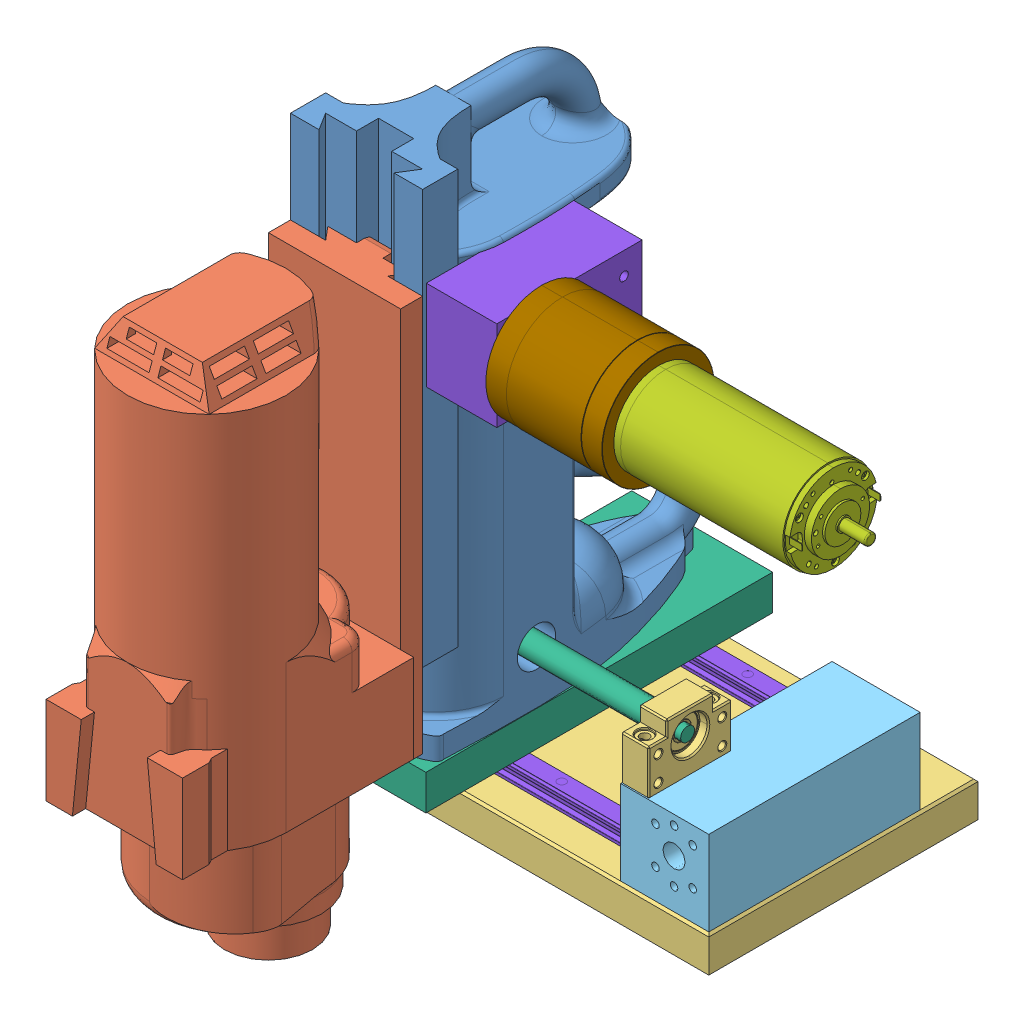
SolidWorks assembly Drill Assembly.12.21.2020, configuration Default. Lengths in mm.
Overall size (544.24 450.85 424.08).
33 component instances, 28 part files, 27 mates.
Components (placement in the parent):
- DrillPressRough-1: DrillPressRough [Default] at (-368.4719 -220.6024 612.8158) x (1 0 0) z (0 1 0) size (105.96 250.99 361.95)
- Motor-1: Motor [Default] at (-110.8779 -309.5024 330.761) x (-1 0 0) z (0 -1 0) size (114.3 193.67 403.23)
- ScrewAssembly_15cm_TOP-1: ScrewAssembly_15cm_TOP [Default] at (-199.8075 -207.5024 157.886) x (0 0 -1) z (1 0 0) size (61 107.5 369.65)
  - BF12.step-1: BF12.step [Default] at (-30 0 240.25) size (60 43 20)
  - BK12.step-1: BK12.step [Default] at (-30 0 12.5) size (60 43 30.65)
  - RM1605 Ball Nut STEP.step-1: RM1605 Ball Nut STEP.step [Default] at (-30 25 30.15) x (0 0 1) z (0 -1 0) size (42 48 40)
  - RM1605-1: RM1605 [Smaller Versionn] at (-30 25 248.25) x (-0.470167 -0.882577 0) z (0 0 -1) size (16 16 275.75)
  - Carriage-1: Carriage [Default] at (-30 -62.5 159.8307) x (1 0 0) z (0 1 0) size (52 63.99 19.5)
  - Rail-1: Rail [Default] at (-30 -62.5 230) x (1 0 0) z (0 1 0) size (15 205 12.5)
  - Gantry Motor.stp-1: Gantry Motor.stp [Default] at (-30 25 -41) x (0 0 -1) z (1 0 0) size (91.9 29 40.5)
    - 0.stp-1: 0.stp [Default] at origin size (14.5 4 4)
    - 0-0.stp-1: 0-0.stp [Default] at origin size (4 12 12)
    - 0-1.stp-1: 0-1.stp [Default] at origin size (10.45 19 19)
    - 0-2.stp-1: 0-2.stp [Default] at origin size (17.97 19 19)
    - 0-3.stp-1: 0-3.stp [Default] at origin size (0.5 9.2 9.2)
    - 0-4.stp-1: 0-4.stp [Default] at origin size (2.88 10 10)
    - 0-5.stp-1: 0-5.stp [Default] at origin size (10.9 17.48 36)
    - 0-6.stp-1: 0-6.stp [Default] at origin size (2 15.64 15.71)
    - 0-7.stp-1: 0-7.stp [Default] at origin size (2.2 29 2.3)
    - 0-8.stp-1: 0-8.stp [Default] at origin size (2.1 15.8 15.45)
    - 0-9.stp-1: 0-9.stp [Default] at origin size (37.3 16 16)
  - Motor Mounting Bracket-1: Motor Mounting Bracket [8982K701] at (-20.5 0 -21.95) x (0 0 -1) z (1 0 0) size (38.1 38.1 19)
- RailMounting-1: RailMounting [Default] at (-95.1825 -295.4024 217.886) x (-1 0 0) z (0 -1 0) size (334.5 194.1 25.4)
- Screw Mounting Major-1: Screw Mounting Major [Default] at (-95.1825 -295.4024 217.886) x (-1 0 0) z (0 -1 0) size (66 152.4 62.5)
- Screw Mounting Minor-1: Screw Mounting Minor [Default] at (-95.1825 -295.4024 217.886) x (-1 0 0) z (0 -1 0) size (63.5 152.4 62.5)
- Rail-1: Rail [Default] at (30.1925 -270.0024 53.786) x (0 0 -1) z (0 1 0) size (15 205 12.5)
- Carriage-1: Carriage [Default] at (-39.9769 -270.0024 53.786) x (0 0 -1) z (0 1 0) size (52 63.99 19.5)
- DrillMounting-2: DrillMounting [Default] at (-110.8779 -220.6024 248.1836) size (105.06 25.4 237.31)
- VerticalMotorAssembly-1: VerticalMotorAssembly [Default] at (83.9982 -43.4879 76.1418) size (302 81 112.87)
  - 353294_RE65_GB_250W_KL_2WE.stp-1: 353294_RE65_GB_250W_KL_2WE.stp [Default] at (-12.2671 92.7605 156.1942) size (185.5 65 65)
  - MotorMounting-1: MotorMounting [Default] at (-147.0671 92.7605 156.1942) x (0 0 -1) z (1 0 0) size (104.77 64.8 50.8)
  - GP81-Stage1.stp-1: GP81-Stage1.stp [Default] at (-12.2671 92.7605 156.1942) size (133.6 81 81)
  - 19mm coupling-1: 19mm coupling [Default] at (-160.9671 92.7605 156.1942) x (0 0 -1) z (1 0 0) size (40 40 55)
Mates (geometry in assembly coordinates):
- Coincident3: coincident aligned: plane of DrillPressRough-1 through (-63.2529 -305.1433 241.861) normal (1 0 0); plane of Motor-1 through (-63.2529 -211.0774 330.761) normal (1 0 0)
- Coincident4: coincident anti-aligned: plane of DrillPressRough-1 through (-63.2529 -305.1433 267.261) normal (0 0 1); plane of Motor-1 through (-110.8779 -211.0774 267.261) normal (0 0 -1)
- Distance2: distance = 88.9 mm aligned: plane of Motor-1 through (-110.8779 -309.5024 330.761) normal (0 -1 0); plane of DrillPressRough-1 through (-368.4719 -220.6024 612.8158) normal (0 -1 0)
- Coincident8: coincident: plane of DrillPressRough-1 through (-159.6575 -220.6024 239.2322) normal (-1 0 0); plane of ScrewAssembly_15cm_TOP-1/RM1605 Ball Nut STEP.step-1 through (-159.6575 -182.5024 187.886) normal (1 0 0)
- Concentric1: concentric: cylinder of DrillPressRough-1 through (-57.4529 -182.5024 187.886) axis (-1 0 0) radius 14; cylinder of ScrewAssembly_15cm_TOP-1/RM1605 Ball Nut STEP.step-1 through (-127.6575 -182.5024 187.886) axis (-1 0 0) radius 14
- Coincident9: coincident anti-aligned: plane of RailMounting-1 through (-95.1825 -270.0024 217.886) normal (0 1 0); plane of Screw Mounting Major-1 through (-95.1825 -270.0024 217.886) normal (0 -1 0)
- Coincident11: coincident aligned: plane of RailMounting-1 through (-240.8075 -270.0024 217.886) normal (-1 0 0); plane of Screw Mounting Major-1 through (-240.8075 -207.5024 217.886) normal (-1 0 0)
- Coincident13: coincident anti-aligned: plane of RailMounting-1 through (-95.1825 -270.0024 217.886) normal (0 1 0); plane of Screw Mounting Minor-1 through (-95.1825 -270.0024 217.886) normal (0 -1 0)
- Coincident14: coincident aligned: plane of Screw Mounting Minor-1 through (93.6925 -270.0024 217.886) normal (1 0 0); plane of RailMounting-1 through (93.6925 -270.0024 217.886) normal (1 0 0)
- Coincident15: coincident aligned: plane of ScrewAssembly_15cm_TOP-1/Motor Mounting Bracket-1 through (-240.8075 -207.5024 197.386) normal (-1 0 0); plane of Screw Mounting Major-1 through (-240.8075 -207.5024 217.886) normal (-1 0 0)
- Coincident16: coincident: plane of ScrewAssembly_15cm_TOP-1/BK12.step-1 through (-174.8075 -175.0024 217.886) normal (0 0 1); plane of Screw Mounting Major-1 through (-95.1825 -207.5024 217.886) normal (0 0 1)
- Coincident17: coincident: plane of ScrewAssembly_15cm_TOP-1/BK12.step-1 through (-174.8075 -207.5024 217.886) normal (0 -1 0); plane of Screw Mounting Major-1 through (-95.1825 -207.5024 217.886) normal (0 1 0)
- Width1: width anti-aligned: plane of Carriage-1 through (-154.6579 -259.9024 46.286) normal (0 0 1); plane of Carriage-1 through (-154.6579 -259.9024 61.286) normal (0 0 -1); plane of Rail-1 through (-174.8075 -264.0993 48.286) normal (0 0 -1); plane of Rail-1 through (-174.8075 -264.0993 59.286) normal (0 0 1)
- Coincident18: coincident anti-aligned: plane of Rail-1 through (-174.8075 -257.5024 53.786) normal (0 1 0); plane of Carriage-1 through (-154.6579 -257.5024 53.786) normal (0 -1 0)
- Coincident19: coincident anti-aligned: plane of Screw Mounting Major-1 through (-174.8075 -207.5024 217.886) normal (1 0 0); plane of Rail-1 through (-174.8075 -263.8538 53.786) normal (-1 0 0)
- Coincident20: coincident aligned: plane of ScrewAssembly_15cm_TOP-1/Rail-1 through (-174.8075 -257.5024 187.886) normal (0 1 0); plane of Rail-1 through (-174.8075 -257.5024 53.786) normal (0 1 0)
- Coincident21: coincident aligned: plane of ScrewAssembly_15cm_TOP-1/Carriage-1 through (-139.2779 -256.1024 187.886) normal (-1 0 0); plane of Carriage-1 through (-139.2779 -256.1024 53.786) normal (-1 0 0)
- Distance3: distance = 88.9 mm: cylinder of Carriage-1 through (-123.8779 -249.5024 74.286) axis (0 -1 0) radius 2.1; cylinder of ScrewAssembly_15cm_TOP-1/Carriage-1 through (-123.8779 -249.5024 167.386) axis (0 -1 0) radius 2.1
- Coincident22: coincident anti-aligned: plane of DrillPressRough-1 through (-368.4719 -220.6024 612.8158) normal (0 -1 0); plane of DrillMounting-2 through (-110.8779 -220.6024 248.1836) normal (0 1 0)
- Concentric2: concentric: cylinder of Carriage-1 through (-123.8779 -249.5024 33.286) axis (0 -1 0) radius 2.1; cylinder of DrillMounting-2 through (-123.8779 -239.6524 33.286) axis (0 -1 0) radius 2.1
- Parallel2: parallel: plane of DrillPressRough-1 through (-368.4719 -204.7274 30.741) normal (0 0 -1); plane of DrillMounting-2 through (-110.8779 -246.0024 18.041) normal (0 0 -1)
- Coincident23: coincident aligned: plane of RailMounting-1 through (-95.1825 -270.0024 217.886) normal (0 0 1); plane of Screw Mounting Minor-1 through (-95.1825 -270.0024 217.886) normal (0 0 1)
- Coincident24: coincident aligned: plane of RailMounting-1 through (-95.1825 -270.0024 217.886) normal (0 0 1); plane of Screw Mounting Major-1 through (-95.1825 -207.5024 217.886) normal (0 0 1)
- Parallel3: parallel aligned: plane of Motor-1 through (-110.8779 -211.0774 283.136) normal (0 0 1); plane of RailMounting-1 through (-95.1825 -270.0024 217.886) normal (0 0 1)
- Concentric3: concentric aligned: cylinder of DrillPressRough-1 through (-164.3029 49.2726 232.336) axis (1 0 0) radius 8.6169; cylinder of VerticalMotorAssembly-1/353294_RE65_GB_250W_KL_2WE.stp-1 through (30.2561 49.2726 232.336) axis (1 0 0) radius 6
- Parallel4: parallel aligned: plane of DrillPressRough-1 through (-368.4719 84.1976 612.8158) normal (0 1 0); plane of VerticalMotorAssembly-1/MotorMounting-1 through (-12.2689 81.6726 264.736) normal (0 1 0)
- Coincident25: coincident anti-aligned: plane of DrillPressRough-1 through (-76.9689 49.2726 232.336) normal (1 0 0); plane of VerticalMotorAssembly-1/19mm coupling-1 through (-76.9689 49.2726 232.336) normal (-1 0 0)
